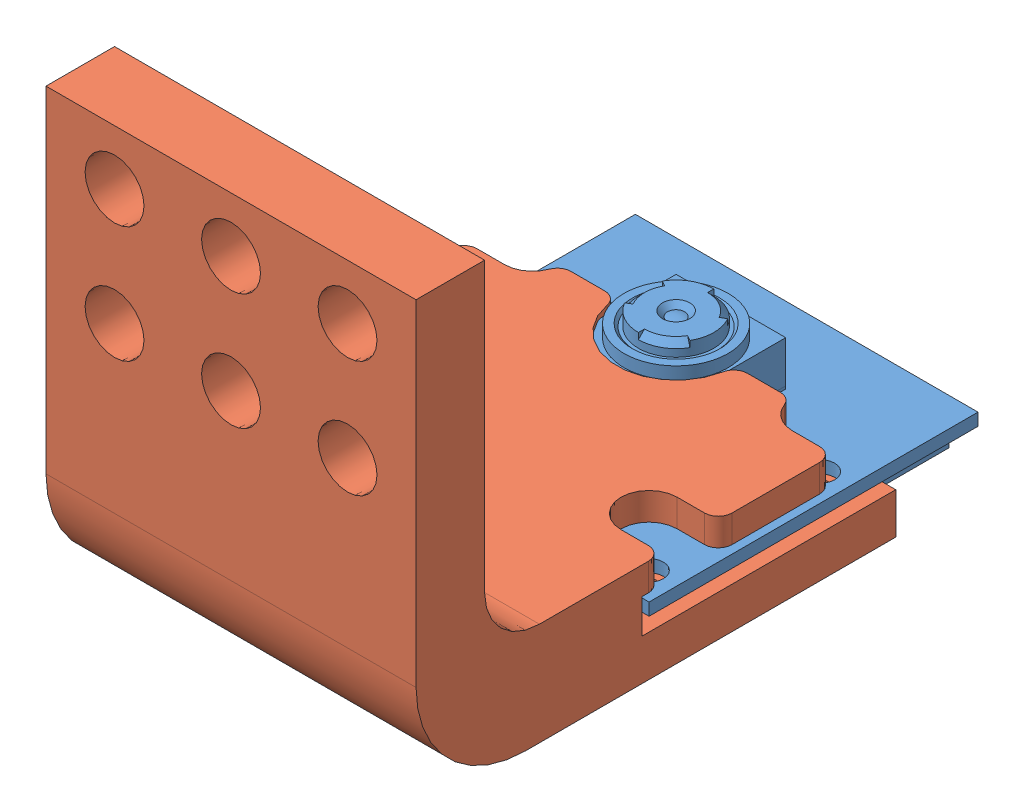
SolidWorks assembly Złożenie1, configuration Domyślna. Lengths in mm.
Overall size (27 32.5 42).
2 component instances, 2 part files, 1 mates.
Components (placement in the parent):
- RasPi_Camera-1: RasPi_Camera [Domyślna] at (-31.753 -1.0067 22.5001) size (25 8.25 24)
- Część8-1: Część8 [Domyślna] at (-18.253 16.6936 -0.5512) size (27 32.5 35)
Mates (geometry in assembly coordinates):
- Odległość1: distance = 1 mm aligned: plane of Część8-1 through (-18.253 16.6936 -0.5512) normal (1 0 0); plane of RasPi_Camera-1 through (-19.253 -2.4584 37.0001) normal (1 0 0)
